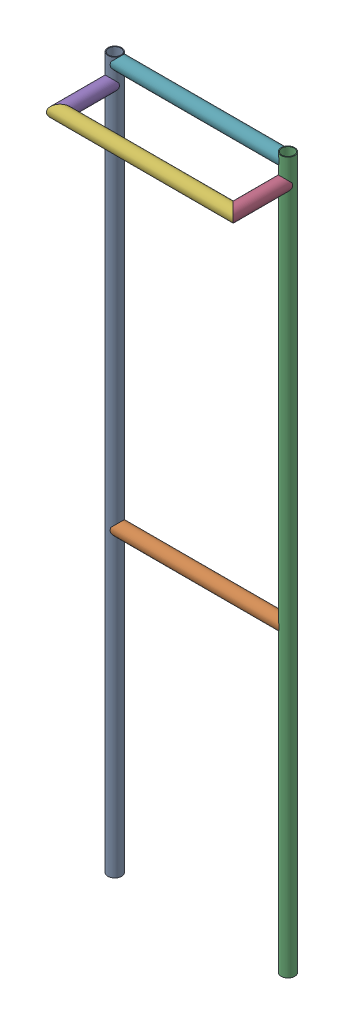
SolidWorks assembly GE-16006_ASM, configuration Default. Lengths in mm.
Overall size (520.7 1981.2 190.5).
7 component instances, 4 part files, 0 mates.
Components (placement in the parent):
- GE-16006-01-1: GE-16006-01 [Default] at origin size (38.1 1981.2 38.1)
- GE-16006-02-1: GE-16006-02 [Default] at (6.35 838.2 0) size (469.9 38.1 38.1)
- GE-16006-01-2: GE-16006-01 [Default] at (482.6 0 0) size (38.1 1981.2 38.1)
- GE-16006-03-1: GE-16006-03 [Default] at (482.6 1911.35 6.35) size (38.1 38.1 165.1)
- GE-16006-03-2: GE-16006-03 [Default] at (0 1911.35 6.35) x (-1 0 0) z (0 0 1) size (38.1 38.1 165.1)
- GE-16006-04-1: GE-16006-04 [Default] at (-19.05 1911.35 152.4) size (520.7 38.1 38.1)
- GE-16006-02-2: GE-16006-02 [Default] at (6.35 1962.15 0) size (469.9 38.1 38.1)
